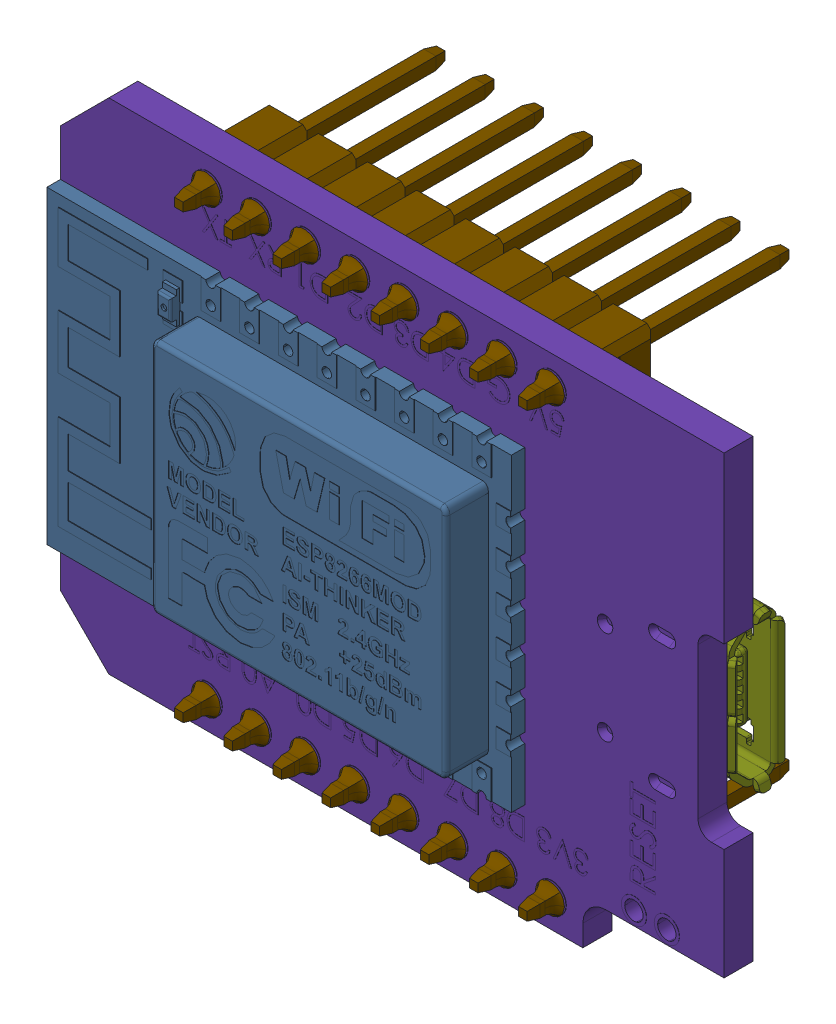
SolidWorks assembly wemos-mini-d1, configuration Default. Lengths in mm.
Overall size (34.3 25.8 14.95).
85 component instances, 37 part files, 0 mates.
Components (placement in the parent):
- wemos-mini-d1.stp-1: wemos-mini-d1.stp [Default] at origin size (34.3 25.8 14.95)
  - WEMOS-MINI-D1_ASM_2_ASM.stp-1: WEMOS-MINI-D1_ASM_2_ASM.stp [Default] at origin size (34.3 25.8 7.11)
    - PRODUCT_13_ASM_2_ASM.stp-1: PRODUCT_13_ASM_2_ASM.stp [Default] at origin size (33.32 19.4 5.55)
      - ASSEMBLY-1002_ASM_1_ASM.stp-1: ASSEMBLY-1002_ASM_1_ASM.stp [По умолчанию] at (-9 0.2 0) x (-1 0 0) z (0 0 -1) size (2.4 3 1)
        - SOT23_ASM_1_ASM.stp-1: SOT23_ASM_1_ASM.stp [По умолчанию] at origin size (2.4 2.34 0.6)
          - SOT23_1_1.stp-1: SOT23_1_1.stp [Default] at origin size (0.6 0.44 0.6)
          - SOT23_2_1.stp-1: SOT23_2_1.stp [Default] at origin size (0.6 0.44 0.6)
          - SOT23_3_1.stp-1: SOT23_3_1.stp [По умолчанию] at origin size (0.6 0.44 0.6)
        - SOT23_001_1.stp-1: SOT23_001_1.stp [По умолчанию] at (0 1.5 0) x (1 0 0) z (0 -1 0) size (1.3 0.9 3)
      - ASSEMBLY-1002_ASM_1_ASM.stp-2: ASSEMBLY-1002_ASM_1_ASM.stp [По умолчанию] at (-1.45 0.2 0) x (1 0 0) z (0 0 -1) size (2.4 3 1)
        - SOT23_ASM_1_ASM.stp-1: SOT23_ASM_1_ASM.stp [По умолчанию] at origin size (2.4 2.34 0.6)
          - SOT23_1_1.stp-1: SOT23_1_1.stp [Default] at origin size (0.6 0.44 0.6)
          - SOT23_2_1.stp-1: SOT23_2_1.stp [Default] at origin size (0.6 0.44 0.6)
          - SOT23_3_1.stp-1: SOT23_3_1.stp [По умолчанию] at origin size (0.6 0.44 0.6)
        - SOT23_001_1.stp-1: SOT23_001_1.stp [По умолчанию] at (0 1.5 0) x (1 0 0) z (0 -1 0) size (1.3 0.9 3)
      - ASSEMBLY-1225_ASM_1_ASM.stp-1: ASSEMBLY-1225_ASM_1_ASM.stp [По умолчанию] at (12.9 9.9 0) x (-1 0 0) z (0 0 -1) size (2.8 3 1)
        - SOT23-5_001_ASM_1_ASM.stp-1: SOT23-5_001_ASM_1_ASM.stp [По умолчанию] at origin size (2.8 2.34 0.59)
          - SOT23-5_001_1_1.stp-1: SOT23-5_001_1_1.stp [По умолчанию] at origin size (0.65 0.44 0.59)
          - SOT23-5_001_2_1.stp-1: SOT23-5_001_2_1.stp [По умолчанию] at origin size (0.65 0.44 0.59)
          - SOT23-5_001_3_1.stp-1: SOT23-5_001_3_1.stp [По умолчанию] at origin size (0.65 0.44 0.59)
          - SOT23-5_001_4_1.stp-1: SOT23-5_001_4_1.stp [По умолчанию] at origin size (0.65 0.44 0.59)
          - SOT23-5_001_5_1.stp-1: SOT23-5_001_5_1.stp [По умолчанию] at origin size (0.65 0.44 0.59)
        - SOT23-5_1.stp-1: SOT23-5_1.stp [По умолчанию] at (0 1.5 0) x (1 0 0) z (0 -1 0) size (1.6 0.91 3)
      - ASSEMBLY-1505_ASM_1_ASM.stp-1: ASSEMBLY-1505_ASM_1_ASM.stp [Default] at (4.75 -0.75 0) x (-1 0 0) z (0 0 -1) size (6 10.02 1.57)
        - SOIC-16_150MIL_001_ASM_1_ASM.stp-1: SOIC-16_150MIL_001_ASM_1_ASM.stp [Default] at origin size (6 9.31 0.97)
          - SOIC-16_150MIL_001_1_1.stp-1: SOIC-16_150MIL_001_1_1.stp [По умолчанию] at origin size (1.3 0.42 0.97)
          - SOIC-16_150MIL_001_2_1.stp-1: SOIC-16_150MIL_001_2_1.stp [По умолчанию] at origin size (1.3 0.42 0.97)
          - SOIC-16_150MIL_001_3_1.stp-1: SOIC-16_150MIL_001_3_1.stp [По умолчанию] at origin size (1.3 0.42 0.97)
          - SOIC-16_150MIL_001_4_1.stp-1: SOIC-16_150MIL_001_4_1.stp [По умолчанию] at origin size (1.3 0.42 0.97)
          - SOIC-16_150MIL_001_5_1.stp-1: SOIC-16_150MIL_001_5_1.stp [По умолчанию] at origin size (1.3 0.42 0.97)
          - SOIC-16_150MIL_001_6_1.stp-1: SOIC-16_150MIL_001_6_1.stp [По умолчанию] at origin size (1.3 0.42 0.97)
          - SOIC-16_150MIL_001_7_1.stp-1: SOIC-16_150MIL_001_7_1.stp [По умолчанию] at origin size (1.3 0.42 0.97)
          - SOIC-16_150MIL_001_8_1.stp-1: SOIC-16_150MIL_001_8_1.stp [По умолчанию] at origin size (1.3 0.42 0.97)
          - SOIC-16_150MIL_001_9_1.stp-1: SOIC-16_150MIL_001_9_1.stp [По умолчанию] at origin size (1.3 0.42 0.97)
          - SOIC-16_150MIL_001_10_1.stp-1: SOIC-16_150MIL_001_10_1.stp [По умолчанию] at origin size (1.3 0.42 0.97)
          - SOIC-16_150MIL_001_11_1.stp-1: SOIC-16_150MIL_001_11_1.stp [По умолчанию] at origin size (1.3 0.42 0.97)
          - SOIC-16_150MIL_001_12_1.stp-1: SOIC-16_150MIL_001_12_1.stp [По умолчанию] at origin size (1.3 0.42 0.97)
          - SOIC-16_150MIL_001_13_1.stp-1: SOIC-16_150MIL_001_13_1.stp [По умолчанию] at origin size (1.3 0.42 0.97)
          - SOIC-16_150MIL_001_14_1.stp-1: SOIC-16_150MIL_001_14_1.stp [Default] at origin size (1.3 0.42 0.97)
          - SOIC-16_150MIL_001_15_1.stp-1: SOIC-16_150MIL_001_15_1.stp [Default] at origin size (1.3 0.42 0.97)
          - SOIC-16_150MIL_001_16_1.stp-1: SOIC-16_150MIL_001_16_1.stp [Default] at origin size (1.3 0.42 0.97)
        - SOIC-16_150MIL_1.stp-1: SOIC-16_150MIL_1.stp [Default] at origin size (3.9 10.02 1.38)
      - PRODUCT_260_3.stp-1: PRODUCT_260_3.stp [Default] at (-5.15 0 1.04) x (0 1 0) z (0 0 1) size (16 24 2.97)
      - RES_0805_1.stp-1: RES_0805_1.stp [Default] at (-10.82 -6.12 0) x (0 -1 0) z (0 0 -1) size (2 1.2 0.5)
      - RES_0805_1.stp-2: RES_0805_1.stp [Default] at (-7.2 -6.12 0) x (0 -1 0) z (0 0 -1) size (2 1.2 0.5)
      - RES_0805_1.stp-3: RES_0805_1.stp [Default] at (-5.39 -6.12 0) x (0 -1 0) z (0 0 -1) size (2 1.2 0.5)
      - RES_0805_1.stp-4: RES_0805_1.stp [Default] at (-3.59 -6.12 0) x (0 -1 0) z (0 0 -1) size (2 1.2 0.5)
      - RES_0805_1.stp-5: RES_0805_1.stp [Default] at (-6.1 0.25 0) x (0 -1 0) z (0 0 -1) size (2 1.2 0.5)
      - RES_0805_1.stp-6: RES_0805_1.stp [Default] at (-4.2 0.25 0) x (0 -1 0) z (0 0 -1) size (2 1.2 0.5)
      - RES_0805_1.stp-7: RES_0805_1.stp [Default] at (-8.96 6.15 0) x (0 -1 0) z (0 0 -1) size (2 1.2 0.5)
      - RES_0805_1.stp-8: RES_0805_1.stp [Default] at (-7.07 6.15 0) x (0 -1 0) z (0 0 -1) size (2 1.2 0.5)
      - RES_0805_1.stp-9: RES_0805_1.stp [Default] at (-0.7 6.35 0) x (0 -1 0) z (0 0 -1) size (2 1.2 0.5)
      - RES_0805_1.stp-10: RES_0805_1.stp [Default] at (1.2 6.35 0) x (0 -1 0) z (0 0 -1) size (2 1.2 0.5)
      - RES_0805_1.stp-11: RES_0805_1.stp [Default] at (3.1 6.35 0) x (0 -1 0) z (0 0 -1) size (2 1.2 0.5)
      - RES_0805_1.stp-12: RES_0805_1.stp [Default] at (15.57 8.45 0) x (0 -1 0) z (0 0 -1) size (2 1.2 0.5)
      - CAP_0805_1.stp-1: CAP_0805_1.stp [Default] at (0.04 -6.1 0) x (0 -1 0) z (0 0 -1) size (2 1.3 1.27)
      - CAP_0805_1.stp-2: CAP_0805_1.stp [Default] at (-1.78 -6.1 0) x (0 -1 0) z (0 0 -1) size (2 1.3 1.27)
      - CAP_0805_1.stp-3: CAP_0805_1.stp [Default] at (-9.01 -6.1 0) x (0 -1 0) z (0 0 -1) size (2 1.3 1.27)
      - CAP_0805_1.stp-4: CAP_0805_1.stp [Default] at (10.3 8.4 0) x (0 -1 0) z (0 0 -1) size (2 1.3 1.27)
      - CAP_0805_1.stp-5: CAP_0805_1.stp [Default] at (14.6 5.35 0) x (1 0 0) z (0 0 -1) size (2 1.3 1.27)
      - CAP_0805_1.stp-6: CAP_0805_1.stp [Default] at (6.8 5.5 0) x (1 0 0) z (0 0 -1) size (2 1.3 1.27)
      - CAP_0805_1.stp-7: CAP_0805_1.stp [Default] at (6.8 7.4 0) x (1 0 0) z (0 0 -1) size (2 1.3 1.27)
      - SOD-323_1.stp-1: SOD-323_1.stp [Default] at (10.8 5.27 0) x (1 0 0) z (0 0 -1) size (2.5 1.25 0.95)
    - WEMOS-D1-MINI_STEP_1_ASM_2_ASM.stp-1: WEMOS-D1-MINI_STEP_1_ASM_2_ASM.stp [Default] at (17.15 12.9 -0.46) x (0 1 0) z (1 0 0) size (25.8 4.22 34.3)
      - COMPONENTS_2_11__2.stp-1: COMPONENTS_2_11__2.stp [Default] at origin size (1 0.5 2.73)
      - _PUSH_BUTTON_-_IMPORTIERT1__2.stp-1: _PUSH_BUTTON_-_IMPORTIERT1__2.stp [Default] at origin size (3.5 1.5 4.6)
      - _USB_SOCKET_-_IMPORTIERT1__2.stp-1: _USB_SOCKET_-_IMPORTIERT1__2.stp [Default] at origin size (8.2 3.3 5.4)
      - PCB_2.stp-1: PCB_2.stp [Default] at origin size (25.8 1.52 34.3)
  - PIN.stp-1: PIN.stp [Default] at (-9.53 11.43 -0.46) x (1 0 0) z (0 1 0) size (2.54 13.54 2.5)
  - PIN.stp-2: PIN.stp [Default] at (-12.07 11.43 -0.46) x (1 0 0) z (0 1 0) size (2.54 13.54 2.5)
  - PIN.stp-3: PIN.stp [Default] at (-14.61 11.43 -0.46) x (1 0 0) z (0 1 0) size (2.54 13.54 2.5)
  - PIN.stp-4: PIN.stp [Default] at (-17.15 11.43 -0.46) x (1 0 0) z (0 1 0) size (2.54 13.54 2.5)
  - PIN.stp-5: PIN.stp [Default] at (-19.69 11.43 -0.46) x (1 0 0) z (0 1 0) size (2.54 13.54 2.5)
  - PIN.stp-6: PIN.stp [Default] at (-22.23 11.43 -0.46) x (1 0 0) z (0 1 0) size (2.54 13.54 2.5)
  - PIN.stp-7: PIN.stp [Default] at (-24.77 11.43 -0.46) x (1 0 0) z (0 1 0) size (2.54 13.54 2.5)
  - PIN.stp-8: PIN.stp [Default] at (-27.31 11.43 -0.46) x (1 0 0) z (0 1 0) size (2.54 13.54 2.5)
  - PIN.stp-9: PIN.stp [Default] at (-9.53 -11.43 -0.46) x (1 0 0) z (0 1 0) size (2.54 13.54 2.5)
  - PIN.stp-10: PIN.stp [Default] at (-12.07 -11.43 -0.46) x (1 0 0) z (0 1 0) size (2.54 13.54 2.5)
  - PIN.stp-11: PIN.stp [Default] at (-14.61 -11.43 -0.46) x (1 0 0) z (0 1 0) size (2.54 13.54 2.5)
  - PIN.stp-12: PIN.stp [Default] at (-17.15 -11.43 -0.46) x (1 0 0) z (0 1 0) size (2.54 13.54 2.5)
  - PIN.stp-13: PIN.stp [Default] at (-19.69 -11.43 -0.46) x (1 0 0) z (0 1 0) size (2.54 13.54 2.5)
  - PIN.stp-14: PIN.stp [Default] at (-22.23 -11.43 -0.46) x (1 0 0) z (0 1 0) size (2.54 13.54 2.5)
  - PIN.stp-15: PIN.stp [Default] at (-24.77 -11.43 -0.46) x (1 0 0) z (0 1 0) size (2.54 13.54 2.5)
  - PIN.stp-16: PIN.stp [Default] at (-27.31 -11.43 -0.46) x (1 0 0) z (0 1 0) size (2.54 13.54 2.5)
  - eBom-prt36.stp-1: eBom-prt36.stp [Default] at origin (suppressed, hidden)
